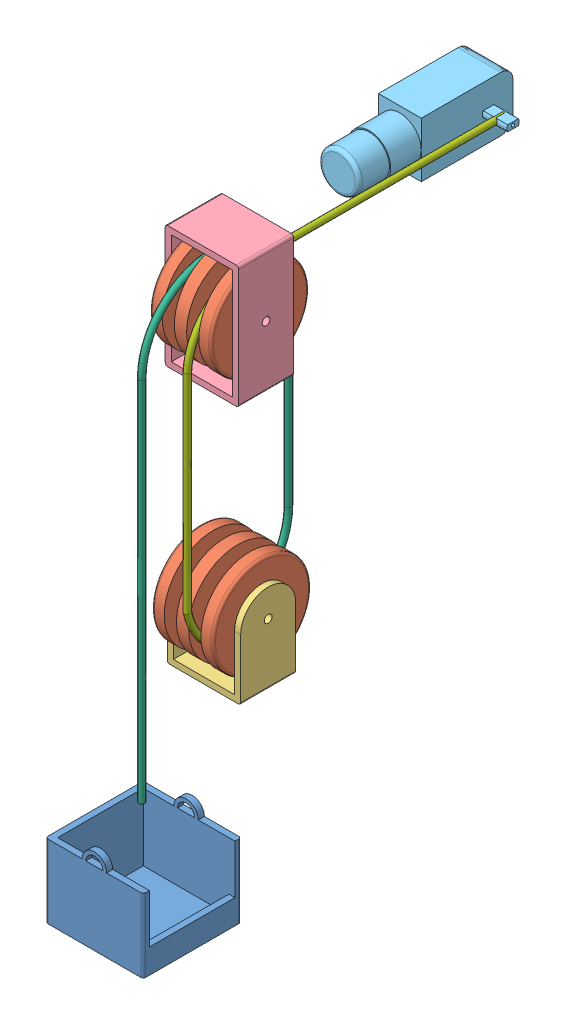
SolidWorks assembly Updated_Pulley, configuration Default. Lengths in mm.
Overall size (43.87 231.53 167.55).
8 component instances, 7 part files, 2 mates.
Components (placement in the parent):
- Updated_Pulley_4-1: Updated_Pulley_4 [Default] at (4.2567 2.3928 37.0028) size (40 35 40)
- Updated_Pulley_1-1: Updated_Pulley_1 [Default] at (-4.6622 208.7152 5.3573) size (25 40 40)
- Updated_Pulley_1-2: Updated_Pulley_1 [Default] at (-4.6421 102.946 4.5335) size (25 40 40)
- Updated_Pulley_3-1: Updated_Pulley_3 [Default] at (-7.1421 102.946 4.5335) size (30 36.25 22.5)
- Updated_Pulley_2-1: Updated_Pulley_2 [Default] at (20.3378 208.7152 5.3573) size (30 50 22.5)
- motor_placeholder-1: motor_placeholder [Default] at (-9.6137 222.6686 -91.7952) size (37.5 22.5 62.5)
- rope1-1: rope1 [Default] at (3.0287 44.2033 36.4159) size (2.5 181.25 62.5)
- rope2-1: rope2 [Default] at (12.5943 87.9084 -2.5648) size (2.5 137.46 130.64)
Mates (geometry in assembly coordinates):
- Coincident1: coincident anti-aligned: circle of Updated_Pulley_1-1; circle of Updated_Pulley_2-1
- Coincident2: coincident aligned: circle of Updated_Pulley_1-2; circle of Updated_Pulley_3-1
